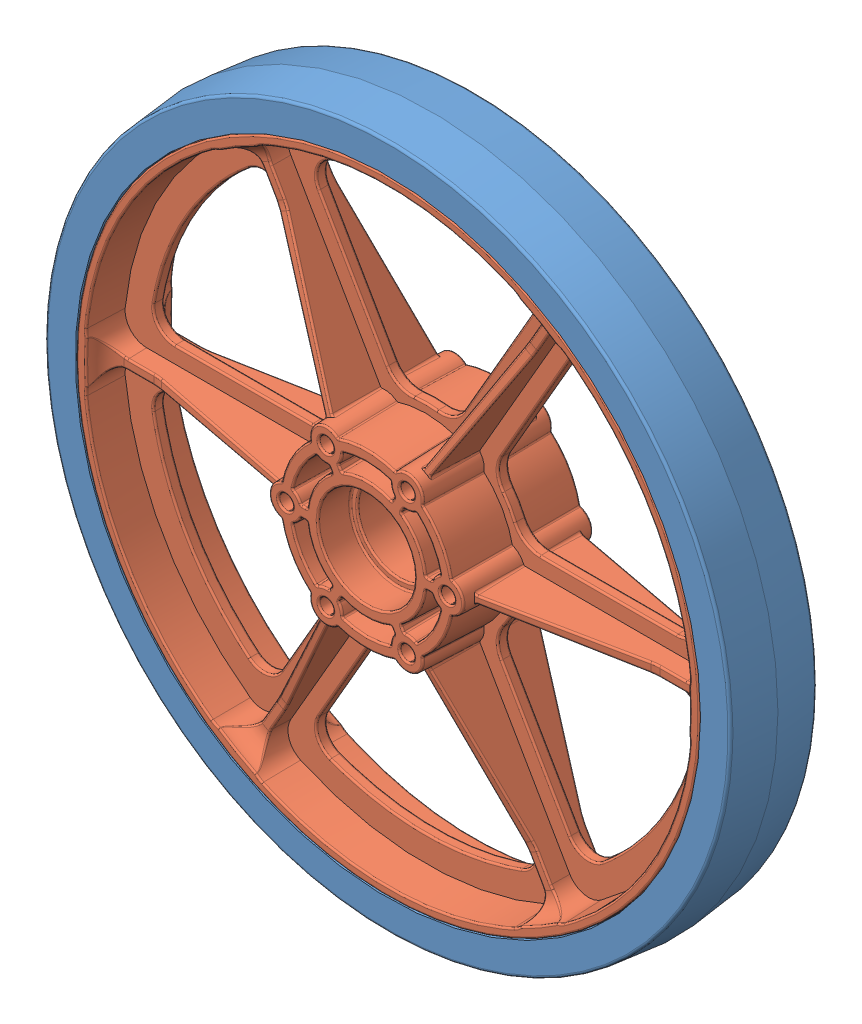
SolidWorks assembly 8Inch_Wheel, configuration Default. Lengths in mm.
Overall size (204.35 204.35 38.11).
2 component instances, 2 part files, 0 mates.
Components (placement in the parent):
- 2010 8 tread-1: 2010 8 tread [Default] at (0 0 12.7) size (204.35 204.35 25.4)
- 2010 8 hub-1: 2010 8 hub [Default] at origin size (190.5 190.5 38.11)
